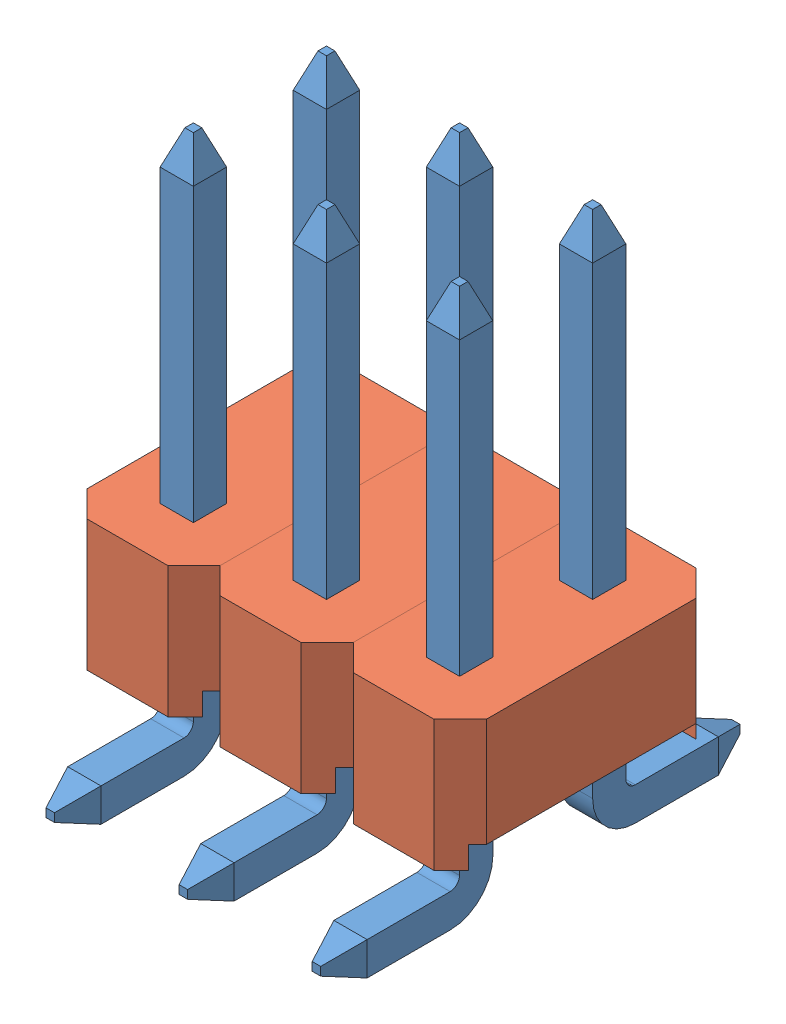
SolidWorks assembly HEADER, PIN, MALE, SMD, 2 Row, 2.54mm Pitch, configuration 6. Lengths in mm.
Overall size (7.62 10.31 8).
9 component instances, 2 part files, 0 mates.
Components (placement in the parent):
- Single pin-1: Single pin [Default] at (0 0 -0.9525)
- Single pin-2: Single pin [Default] at (0.635 0 0.9525) x (-1 0 0) z (0 0 -1)
- Single plastic support-1: Single plastic support [Default] at (1.6 -8.71 1.27) x (0 0 -1) z (1 0 0)
- Single plastic support-11: Single plastic support [Default] at (4.14 -8.71 1.27) x (0 0 -1) z (1 0 0)
- Single pin-21: Single pin [Default] at (3.175 0 0.9525) x (-1 0 0) z (0 0 -1)
- Single pin-22: Single pin [Default] at (2.54 0 -0.9525)
- Single pin-23: Single pin [Default] at (5.08 0 -0.9525)
- Single pin-24: Single pin [Default] at (5.715 0 0.9525) x (-1 0 0) z (0 0 -1)
- Single plastic support-12: Single plastic support [Default] at (6.68 -8.71 1.27) x (0 0 -1) z (1 0 0)
